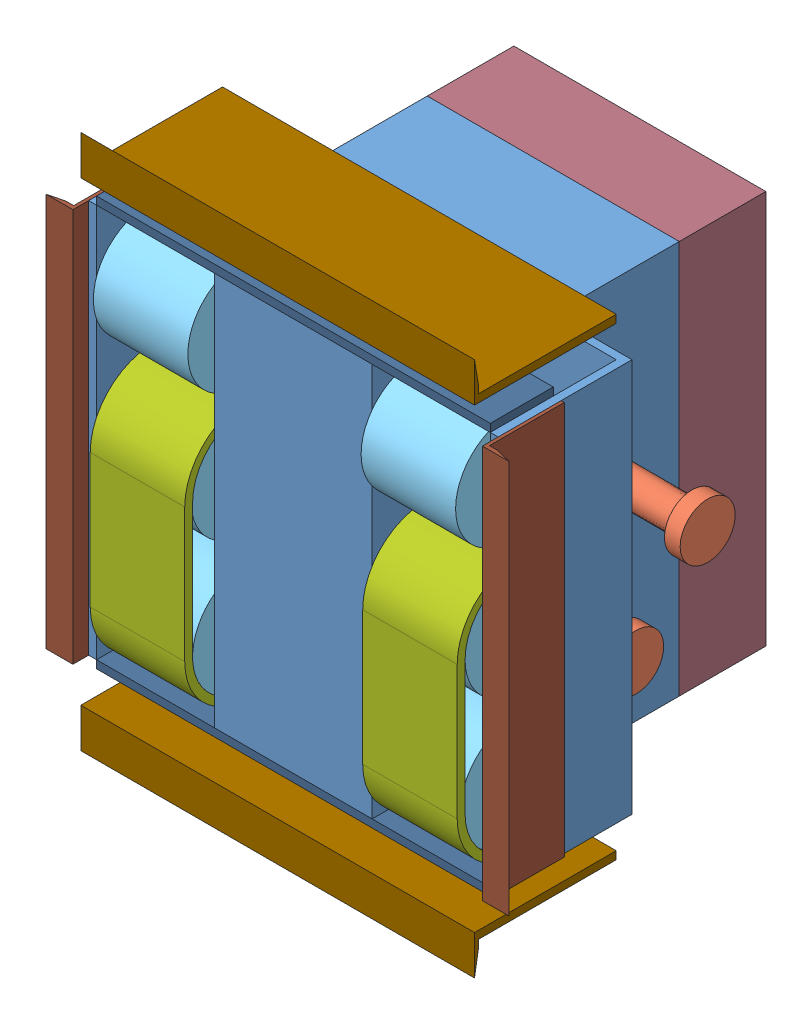
SolidWorks assembly Assemblage1, configuration Défaut. Lengths in mm.
Overall size (295.07 340 206.57).
33 component instances, 15 part files, 79 mates.
Components (placement in the parent):
- CHASSIS INFERIEUR-1: CHASSIS INFERIEUR [Défaut] at (41.3678 -114.8816 337.5001) size (260 250 165)
- verin-1: verin [Défaut] at (114.4382 35.1184 227.5001) x (0 0 1) z (-1 0 0) size (40 40 135)
- verin-2: verin [Défaut] at (-64.5411 -14.8816 227.5001) x (0 1 0) z (1 0 0) size (40 40 135)
- verin-3: verin [Défaut] at (-62.8283 80.1184 227.5001) x (0 0 -1) z (1 0 0) size (40 40 135)
- verin-4: verin [Défaut] at (69.0152 -59.8816 227.5001) x (0 -1 0) z (-1 0 0) size (40 40 135)
- moteur dc-1: moteur dc [Défaut] at (-28.1322 -92.8521 294.8582) x (-1 0 0) z (0 0.999096 -0.042505) size (44 72 145.16)
- moteur dc-2: moteur dc [Défaut] at (20.8678 112.6401 292.734) x (1 0 0) z (0 -0.999761 -0.021843) size (44 72 145.16)
- axe moteur2-1: axe moteur2 [Défaut] at (-35.6322 10.1184 315.5001) x (0 -0.257747 0.966212) z (-1 0 0) size (15 15 90)
- axe moteur2-2: axe moteur2 [Défaut] at (28.3678 10.1184 315.5001) x (0 -0.997153 0.07541) z (1 0 0) size (15 15 90)
- roue70-1: roue70 [Défaut] at (53.3678 10.1184 315.5001) x (0 0 -1) z (1 0 0) size (70 70 60)
- roue70-2: roue70 [Défaut] at (-60.6322 10.1184 315.5001) x (0 0 1) z (-1 0 0) size (70 70 60)
- axe roues-1: axe roues [Défaut] at (110.3678 -74.8816 315.5001) x (0 0.810625 0.585565) z (-1 0 0) size (15.31 15.16 240)
- roue70-3: roue70 [Défaut] at (-59.6322 -74.8816 315.5001) x (0 0 1) z (-1 0 0) size (70 70 60)
- roue70-4: roue70 [Défaut] at (110.3678 -74.8816 315.5001) x (0 -0.558004 0.829838) z (-1 0 0) size (70 70 60)
- roue70-5: roue70 [Défaut] at (-117.6322 95.1184 320.5001) x (0 0 -1) z (1 0 0) size (70 70 60)
- roue70-6: roue70 [Défaut] at (52.3678 95.1184 320.5001) x (0 0 -1) z (1 0 0) size (70 70 60)
- axe roues-2: axe roues [Défaut] at (-117.6322 95.1184 320.5001) x (0 -0.953529 0.3013) z (1 0 0) size (15.31 15.16 240)
- courroie-1: courroie [Défaut] at (53.3678 -74.8816 315.5001) x (0 1 0) z (1 0 0) size (165 80 60)
- appuie pare-1: appuie pare [Défaut] at (46.3678 135.1184 297.5001) x (1 0 0) z (0 1 0) size (90 35 20)
- pare avant-1: pare avant [Défaut] at (121.3678 155.1184 352.5001) x (1 0 0) z (0 1 0) size (250 90 25)
- appuie pare-3: appuie pare [Défaut] at (46.3678 -114.8816 262.5001) x (1 0 0) z (0 -1 0) size (90 35 20)
- pare avant-3: pare avant [Défaut] at (-128.6322 -134.8816 352.5001) x (-1 0 0) z (0 -1 0) size (250 90 25)
- suport capteurs-1: suport capteurs [Défaut] at (121.3678 135.1184 342.5001) x (1 0 0) z (0 1 0) size (250 40 5)
- suport capteurs-2: suport capteurs [Défaut] at (121.3678 -119.8816 342.5001) x (1 0 0) z (0 1 0) size (250 40 5)
- pare coté-1: pare coté [Défaut] at (-133.6322 135.1184 352.5001) x (0 1 0) z (-1 0 0) size (250 50 17)
- pare coté-2: pare coté [Défaut] at (126.3678 -114.8816 352.5001) x (0 -1 0) z (1 0 0) size (250 50 17)
- courroie-2: courroie [Défaut] at (-119.6322 -74.8816 315.5001) x (0 1 0) z (1 0 0) size (165 80 60)
- appuie verin-1: appuie verin [Défaut] at (-53.6322 -109.8816 257.5001) x (0 -1 0) z (1 0 0) size (240 100 5)
- appuie verin-2: appuie verin [Défaut] at (46.3678 130.1184 257.5001) x (0 1 0) z (-1 0 0) size (240 100 5)
- chassis superieur-2: chassis superieur [Défaut] at (-83.6322 -114.8816 177.5001) x (-1 0 0) z (0 0 -1) size (160 250 55) (hidden)
- moteur verin-1: moteur verin [Défaut] at (71.3678 37.6184 195.0001) x (0 0.993394 -0.114755) z (-1 0 0) size (25 25 25)
- moteur verin-2: moteur verin [Défaut] at (-78.6322 -17.3816 175.0001) x (0 -0.999164 -0.040883) z (1 0 0) size (25 25 25)
- attache verin-1: attache verin [Défaut] at (-38.6322 -17.8816 174.8001) x (0 -0.217009 -0.97617) z (1 0 0) size (64.01 75.98 25)
Mates (geometry in assembly coordinates):
- Coaxiale1: concentric anti-aligned: cylinder of CHASSIS INFERIEUR-1 through (-3.6322 35.1184 227.5001) axis (1 0 0) radius 20; cylinder of verin-1 through (144.4382 35.1184 227.5001) axis (-1 0 0) radius 17.5
- Coaxiale2: concentric anti-aligned: cylinder of CHASSIS INFERIEUR-1 through (-3.6322 -59.8816 227.5001) axis (1 0 0) radius 20; cylinder of verin-4 through (99.0152 -59.8816 227.5001) axis (-1 0 0) radius 17.5
- Coaxiale3: concentric anti-aligned: cylinder of CHASSIS INFERIEUR-1 through (-73.6322 80.1184 227.5001) axis (-1 0 0) radius 20; cylinder of verin-3 through (-92.8283 80.1184 227.5001) axis (1 0 0) radius 17.5
- Coaxiale4: concentric anti-aligned: cylinder of CHASSIS INFERIEUR-1 through (-73.6322 -14.8816 227.5001) axis (-1 0 0) radius 20; cylinder of verin-2 through (-94.5411 -14.8816 227.5001) axis (1 0 0) radius 17.5
- Coïncidente1: coincident aligned: plane of verin-2 through (40.4589 -34.8816 207.5001) normal (0 0 -1); plane of verin-3 through (42.1717 100.1184 207.5001) normal (0 0 -1)
- Coïncidente2: coincident aligned: plane of verin-1 through (9.4382 55.1184 207.5001) normal (0 0 -1); plane of verin-4 through (-35.9848 -39.8816 207.5001) normal (0 0 -1)
- Coaxiale5: concentric anti-aligned: cylinder of CHASSIS INFERIEUR-1 through (-48.6322 10.1184 315.5001) axis (-1 0 0) radius 10; cylinder of moteur dc-1 through (-45.6322 10.1184 315.5001) axis (1 0 0) radius 5.5
- Coïncidente3: coincident anti-aligned: plane of CHASSIS INFERIEUR-1 through (-48.6322 -114.8816 337.5001) normal (1 0 0); plane of moteur dc-1 through (-48.6322 20.345 298.0594) normal (-1 0 0)
- Coaxiale6: concentric anti-aligned: cylinder of CHASSIS INFERIEUR-1 through (41.3678 10.1184 315.5001) axis (1 0 0) radius 10; cylinder of moteur dc-2 through (38.3678 10.1184 315.5001) axis (-1 0 0) radius 5.5
- Coïncidente4: coincident anti-aligned: plane of CHASSIS INFERIEUR-1 through (41.3678 -114.8816 337.5001) normal (-1 0 0); plane of moteur dc-2 through (41.3678 30.3286 314.946) normal (1 0 0)
- Coaxiale7: concentric aligned: cylinder of moteur dc-1 through (-45.6322 10.1184 315.5001) axis (1 0 0) radius 5.5; cylinder of axe moteur2-1 through (-120.6322 10.1184 315.5001) axis (1 0 0) radius 5
- Coïncidente5: coincident anti-aligned: plane of moteur dc-1 through (-35.6322 -92.8521 294.8582) normal (-1 0 0); plane of axe moteur2-1 through (-35.6322 10.1184 315.5001) normal (1 0 0)
- Coaxiale8: concentric aligned: cylinder of moteur dc-2 through (38.3678 10.1184 315.5001) axis (-1 0 0) radius 5.5; cylinder of axe moteur2-2 through (113.3678 10.1184 315.5001) axis (-1 0 0) radius 5
- Coïncidente6: coincident anti-aligned: plane of moteur dc-2 through (28.3678 112.6401 292.734) normal (1 0 0); plane of axe moteur2-2 through (28.3678 10.1184 315.5001) normal (-1 0 0)
- Coaxiale9: concentric anti-aligned: cylinder of axe moteur2-2 through (113.3678 10.1184 315.5001) axis (-1 0 0) radius 5; cylinder of roue70-1 through (53.3678 10.1184 315.5001) axis (1 0 0) radius 5
- Coïncidente7: coincident anti-aligned: plane of axe moteur2-2 through (113.3678 10.1184 315.5001) normal (-1 0 0); plane of roue70-1 through (113.3678 10.1184 315.5001) normal (1 0 0)
- Coaxiale10: concentric anti-aligned: cylinder of axe moteur2-1 through (-120.6322 10.1184 315.5001) axis (1 0 0) radius 5; cylinder of roue70-2 through (-60.6322 10.1184 315.5001) axis (-1 0 0) radius 5
- Coïncidente8: coincident anti-aligned: plane of axe moteur2-1 through (-120.6322 10.1184 315.5001) normal (1 0 0); plane of roue70-2 through (-120.6322 10.1184 315.5001) normal (-1 0 0)
- Coaxiale11: concentric anti-aligned: cylinder of CHASSIS INFERIEUR-1 through (-48.6322 -74.8816 315.5001) axis (-1 0 0) radius 10; cylinder of axe roues-1 through (-119.6322 -74.8816 315.5001) axis (1 0 0) radius 5
- Distance1: distance = 1 mm anti-aligned: plane of axe roues-1 through (-54.6322 -74.8816 315.5001) normal (1 0 0); plane of CHASSIS INFERIEUR-1 through (-53.6322 -114.8816 337.5001) normal (-1 0 0)
- Coaxiale12: concentric anti-aligned: cylinder of axe roues-1 through (-119.6322 -74.8816 315.5001) axis (1 0 0) radius 5; cylinder of roue70-4 through (110.3678 -74.8816 315.5001) axis (-1 0 0) radius 5
- Coïncidente10: coincident anti-aligned: plane of axe roues-1 through (50.3678 -74.8816 315.5001) normal (1 0 0); plane of roue70-4 through (50.3678 -74.8816 315.5001) normal (-1 0 0)
- Coaxiale13: concentric anti-aligned: cylinder of axe roues-1 through (-119.6322 -74.8816 315.5001) axis (1 0 0) radius 5; cylinder of roue70-3 through (-59.6322 -74.8816 315.5001) axis (-1 0 0) radius 5
- Coïncidente11: coincident anti-aligned: plane of axe roues-1 through (-119.6322 -74.8816 315.5001) normal (1 0 0); plane of roue70-3 through (-119.6322 -74.8816 315.5001) normal (-1 0 0)
- Coaxiale14: concentric anti-aligned: cylinder of CHASSIS INFERIEUR-1 through (41.3678 95.1184 320.5001) axis (1 0 0) radius 10; cylinder of axe roues-2 through (112.3678 95.1184 320.5001) axis (-1 0 0) radius 5
- Distance3: distance = 1 mm anti-aligned: plane of axe roues-2 through (47.3678 95.1184 320.5001) normal (-1 0 0); plane of CHASSIS INFERIEUR-1 through (46.3678 -114.8816 337.5001) normal (1 0 0)
- Coaxiale15: concentric anti-aligned: cylinder of roue70-5 through (-117.6322 95.1184 320.5001) axis (1 0 0) radius 5; cylinder of axe roues-2 through (112.3678 95.1184 320.5001) axis (-1 0 0) radius 5
- Coïncidente14: coincident anti-aligned: plane of roue70-5 through (-117.6322 95.1184 320.5001) normal (-1 0 0); plane of axe roues-2 through (-117.6322 95.1184 320.5001) normal (1 0 0)
- Coaxiale16: concentric anti-aligned: cylinder of roue70-6 through (52.3678 95.1184 320.5001) axis (1 0 0) radius 5; cylinder of axe roues-2 through (112.3678 95.1184 320.5001) axis (-1 0 0) radius 5
- Coïncidente15: coincident anti-aligned: plane of roue70-6 through (52.3678 95.1184 320.5001) normal (-1 0 0); plane of axe roues-2 through (52.3678 95.1184 320.5001) normal (1 0 0)
- Coaxiale17: concentric anti-aligned: cylinder of roue70-4 through (50.3678 -74.8816 315.5001) axis (1 0 0) radius 35; cylinder of courroie-1 through (113.3678 -74.8816 315.5001) axis (-1 0 0) radius 35
- Coaxiale18: concentric aligned: cylinder of roue70-1 through (113.3678 10.1184 315.5001) axis (-1 0 0) radius 35; cylinder of courroie-1 through (113.3678 10.1184 315.5001) axis (-1 0 0) radius 35
- Coïncidente16: coincident aligned: plane of roue70-1 through (113.3678 10.1184 315.5001) normal (1 0 0); plane of courroie-1 through (113.3678 -74.8816 315.5001) normal (1 0 0)
- Coïncidente17: coincident anti-aligned: plane of CHASSIS INFERIEUR-1 through (41.3678 135.1184 342.5001) normal (0 1 0); plane of appuie pare-1 through (46.3678 135.1184 297.5001) normal (0 -1 0)
- Coïncidente18: coincident aligned: plane of CHASSIS INFERIEUR-1 through (46.3678 -114.8816 337.5001) normal (1 0 0); plane of appuie pare-1 through (46.3678 155.1184 297.5001) normal (1 0 0)
- Coïncidente19: coincident anti-aligned: plane of CHASSIS INFERIEUR-1 through (41.3678 -114.8816 262.5001) normal (0 0 1); plane of appuie pare-1 through (46.3678 155.1184 262.5001) normal (0 0 -1)
- Coïncidente20: coincident anti-aligned: plane of appuie pare-1 through (46.3678 155.1184 297.5001) normal (0 1 0); plane of pare avant-1 through (121.3678 155.1184 352.5001) normal (0 -1 0)
- Coïncidente21: coincident aligned: plane of appuie pare-1 through (46.3678 155.1184 262.5001) normal (0 0 -1); plane of pare avant-1 through (121.3678 160.1184 262.5001) normal (0 0 -1)
- Coïncidente22: coincident anti-aligned: plane of CHASSIS INFERIEUR-1 through (121.3678 -114.8816 337.5001) normal (-1 0 0); plane of pare avant-1 through (121.3678 160.1184 352.5001) normal (1 0 0)
- Coïncidente23: coincident anti-aligned: plane of CHASSIS INFERIEUR-1 through (41.3678 -114.8816 342.5001) normal (0 -1 0); plane of appuie pare-3 through (46.3678 -114.8816 262.5001) normal (0 1 0)
- Coïncidente24: coincident anti-aligned: plane of CHASSIS INFERIEUR-1 through (41.3678 -114.8816 262.5001) normal (0 0 1); plane of appuie pare-3 through (46.3678 -134.8816 262.5001) normal (0 0 -1)
- Coïncidente25: coincident aligned: plane of CHASSIS INFERIEUR-1 through (46.3678 -114.8816 337.5001) normal (1 0 0); plane of appuie pare-3 through (46.3678 -134.8816 262.5001) normal (1 0 0)
- Coïncidente26: coincident anti-aligned: plane of appuie pare-3 through (46.3678 -134.8816 262.5001) normal (0 -1 0); plane of pare avant-3 through (-128.6322 -134.8816 352.5001) normal (0 1 0)
- Coïncidente27: coincident aligned: plane of appuie pare-3 through (46.3678 -134.8816 262.5001) normal (0 0 -1); plane of pare avant-3 through (-128.6322 -139.8816 262.5001) normal (0 0 -1)
- Coïncidente28: coincident anti-aligned: plane of CHASSIS INFERIEUR-1 through (-128.6322 -114.8816 337.5001) normal (1 0 0); plane of pare avant-3 through (-128.6322 -139.8816 352.5001) normal (-1 0 0)
- Coïncidente29: coincident anti-aligned: plane of CHASSIS INFERIEUR-1 through (41.3678 135.1184 342.5001) normal (0 1 0); plane of suport capteurs-1 through (121.3678 135.1184 342.5001) normal (0 -1 0)
- Coïncidente30: coincident aligned: plane of CHASSIS INFERIEUR-1 through (41.3678 -114.8816 342.5001) normal (0 0 1); plane of suport capteurs-1 through (121.3678 140.1184 342.5001) normal (0 0 1)
- Coïncidente31: coincident aligned: plane of pare avant-1 through (121.3678 160.1184 352.5001) normal (1 0 0); plane of suport capteurs-1 through (121.3678 140.1184 342.5001) normal (1 0 0)
- Coïncidente32: coincident anti-aligned: plane of CHASSIS INFERIEUR-1 through (41.3678 -114.8816 342.5001) normal (0 -1 0); plane of suport capteurs-2 through (121.3678 -114.8816 342.5001) normal (0 1 0)
- Coïncidente33: coincident aligned: plane of pare avant-3 through (121.3678 -139.8816 352.5001) normal (1 0 0); plane of suport capteurs-2 through (121.3678 -114.8816 342.5001) normal (1 0 0)
- Coïncidente34: coincident aligned: plane of CHASSIS INFERIEUR-1 through (41.3678 -114.8816 342.5001) normal (0 0 1); plane of suport capteurs-2 through (121.3678 -114.8816 342.5001) normal (0 0 1)
- Coïncidente35: coincident anti-aligned: plane of CHASSIS INFERIEUR-1 through (126.3678 -114.8816 337.5001) normal (1 0 0); plane of pare coté-2 through (126.3678 -114.8816 352.5001) normal (-1 0 0)
- Coïncidente36: coincident aligned: plane of pare avant-1 through (121.3678 160.1184 352.5001) normal (0 0 1); plane of pare coté-2 through (128.3678 -114.8816 352.5001) normal (0 0 1)
- Coïncidente37: coincident aligned: plane of CHASSIS INFERIEUR-1 through (41.3678 -114.8816 342.5001) normal (0 -1 0); plane of pare coté-2 through (128.3678 -114.8816 352.5001) normal (0 -1 0)
- Coïncidente38: coincident anti-aligned: plane of CHASSIS INFERIEUR-1 through (-133.6322 -114.8816 337.5001) normal (-1 0 0); plane of pare coté-1 through (-133.6322 135.1184 352.5001) normal (1 0 0)
- Coïncidente39: coincident aligned: plane of pare avant-3 through (-128.6322 -139.8816 352.5001) normal (0 0 1); plane of pare coté-1 through (-135.6322 135.1184 352.5001) normal (0 0 1)
- Coïncidente40: coincident aligned: plane of CHASSIS INFERIEUR-1 through (41.3678 -114.8816 342.5001) normal (0 -1 0); plane of pare coté-1 through (-135.6322 -114.8816 352.5001) normal (0 -1 0)
- Coaxiale19: concentric anti-aligned: cylinder of roue70-2 through (-120.6322 10.1184 315.5001) axis (1 0 0) radius 35; cylinder of courroie-2 through (-59.6322 10.1184 315.5001) axis (-1 0 0) radius 35
- Coaxiale20: concentric anti-aligned: cylinder of roue70-3 through (-119.6322 -74.8816 315.5001) axis (1 0 0) radius 35; cylinder of courroie-2 through (-59.6322 -74.8816 315.5001) axis (-1 0 0) radius 35
- Coïncidente41: coincident aligned: plane of roue70-3 through (-119.6322 -74.8816 315.5001) normal (-1 0 0); plane of courroie-2 through (-119.6322 -74.8816 315.5001) normal (-1 0 0)
- Parallèle1: parallel anti-aligned: plane of CHASSIS INFERIEUR-1 through (-78.6322 135.1184 177.5001) normal (1 0 0); plane of appuie verin-1 through (-53.6322 -109.8816 257.5001) normal (-1 0 0)
- Coïncidente47: coincident anti-aligned: plane of CHASSIS INFERIEUR-1 through (41.3678 -109.8816 337.5001) normal (0 1 0); plane of appuie verin-1 through (-48.6322 -109.8816 257.5001) normal (0 -1 0)
- Parallèle3: parallel anti-aligned: plane of CHASSIS INFERIEUR-1 through (71.3678 135.1184 177.5001) normal (-1 0 0); plane of appuie verin-2 through (46.3678 130.1184 257.5001) normal (1 0 0)
- Coïncidente51: coincident anti-aligned: plane of CHASSIS INFERIEUR-1 through (41.3678 -109.8816 337.5001) normal (0 1 0); plane of appuie verin-2 through (41.3678 -109.8816 257.5001) normal (0 -1 0)
- Coïncidente52: coincident aligned: plane of CHASSIS INFERIEUR-1 through (41.3678 -114.8816 337.5001) normal (-1 0 0); plane of appuie verin-2 through (41.3678 130.1184 257.5001) normal (-1 0 0)
- Coïncidente53: coincident anti-aligned: plane of CHASSIS INFERIEUR-1 through (41.3678 -114.8816 257.5001) normal (0 0 -1); plane of appuie verin-2 through (41.3678 130.1184 257.5001) normal (0 0 1)
- Coïncidente56: coincident anti-aligned: plane of CHASSIS INFERIEUR-1 through (-48.6322 -114.8816 257.5001) normal (0 0 -1); plane of appuie verin-1 through (-48.6322 -109.8816 257.5001) normal (0 0 1)
- Coïncidente58: coincident anti-aligned: plane of CHASSIS INFERIEUR-1 through (41.3678 -114.8816 177.5001) normal (0 0 -1); plane of chassis superieur-2 through (-83.6322 -114.8816 177.5001) normal (0 0 1)
- Coïncidente59: coincident aligned: plane of CHASSIS INFERIEUR-1 through (76.3678 135.1184 177.5001) normal (1 0 0); plane of chassis superieur-2 through (76.3678 -114.8816 127.5001) normal (1 0 0)
- Coïncidente60: coincident aligned: plane of CHASSIS INFERIEUR-1 through (41.3678 -114.8816 342.5001) normal (0 -1 0); plane of chassis superieur-2 through (-83.6322 -114.8816 127.5001) normal (0 -1 0)
- Coïncidente61: coincident aligned: plane of CHASSIS INFERIEUR-1 through (-48.6322 -114.8816 337.5001) normal (1 0 0); plane of appuie verin-1 through (-48.6322 -109.8816 257.5001) normal (1 0 0)
- Coïncidente62: coincident anti-aligned: plane of CHASSIS INFERIEUR-1 through (-78.6322 135.1184 177.5001) normal (1 0 0); plane of moteur verin-2 through (-78.6322 -17.3816 175.0001) normal (-1 0 0)
- Coïncidente63: coincident anti-aligned: plane of CHASSIS INFERIEUR-1 through (71.3678 135.1184 177.5001) normal (-1 0 0); plane of moteur verin-1 through (71.3678 37.6184 195.0001) normal (1 0 0)
- Distance10: distance = 80 mm anti-aligned: cylinder of moteur verin-1 through (46.3678 37.6184 195.0001) axis (1 0 0) radius 12.5; plane of CHASSIS INFERIEUR-1 through (41.3678 130.1184 337.5001) normal (0 -1 0)
- Distance11: distance = 50 mm anti-aligned: cylinder of moteur verin-1 through (46.3678 37.6184 195.0001) axis (1 0 0) radius 12.5; plane of CHASSIS INFERIEUR-1 through (41.3678 -114.8816 257.5001) normal (0 0 -1)
- Distance12: distance = 80 mm anti-aligned: cylinder of moteur verin-2 through (-53.6322 -17.3816 175.0001) axis (-1 0 0) radius 12.5; plane of CHASSIS INFERIEUR-1 through (41.3678 -109.8816 337.5001) normal (0 1 0)
- Distance13: distance = 70 mm anti-aligned: cylinder of moteur verin-2 through (-53.6322 -17.3816 175.0001) axis (-1 0 0) radius 12.5; plane of CHASSIS INFERIEUR-1 through (-48.6322 -114.8816 257.5001) normal (0 0 -1)
- Coaxiale29: concentric aligned: cylinder of appuie verin-1 through (-53.6322 -17.8816 174.8001) axis (1 0 0) radius 5; cylinder of attache verin-1 through (-58.6322 -17.8816 174.8001) axis (1 0 0) radius 5
- Coïncidente64: coincident anti-aligned: plane of moteur verin-2 through (-58.6322 -17.3816 175.0001) normal (1 0 0); plane of attache verin-1 through (-58.6322 -17.8816 174.8001) normal (-1 0 0)
